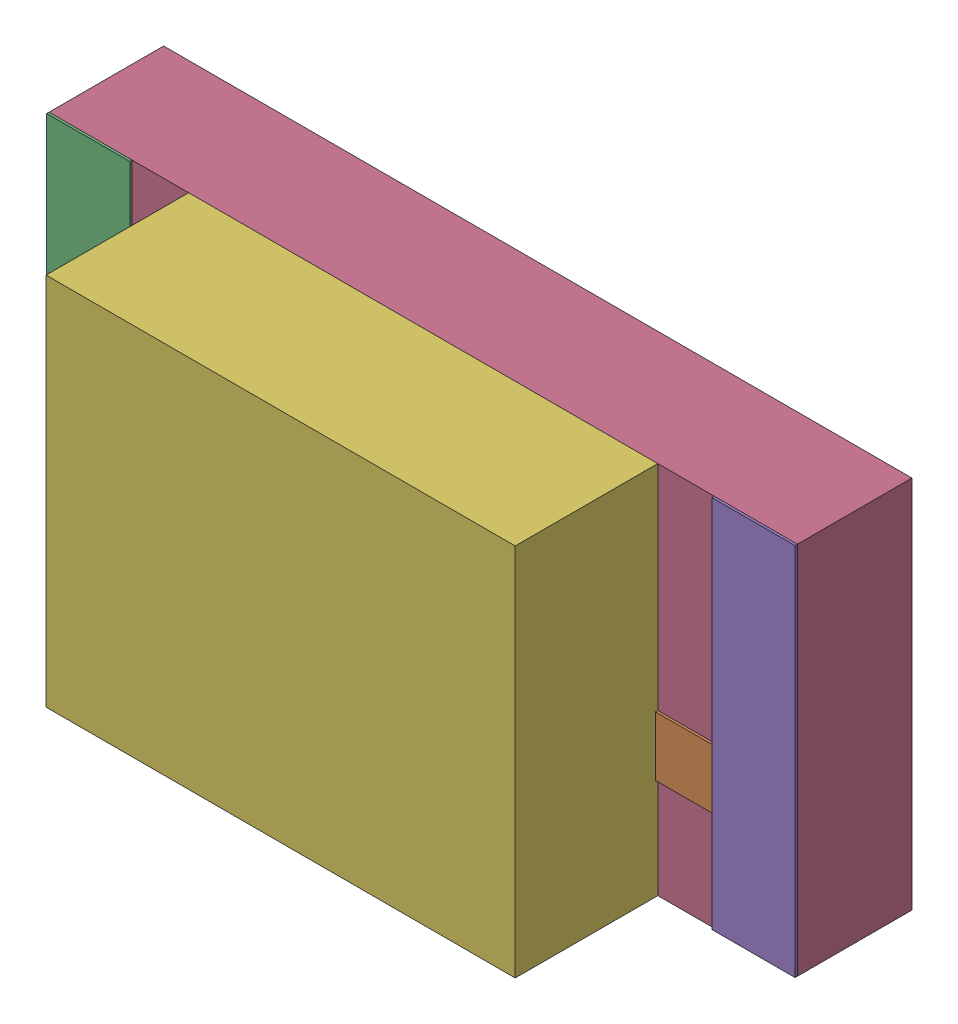
SolidWorks assembly SW3dPS-LED1206G_Open_CASCADE_STEP_translator_6.2_262.2, configuration Défaut. Lengths in mm.
Overall size (3.2 1.6 1.1).
12 component instances, 5 part files, 0 mates.
Components (placement in the parent):
- SW3dPS-LED1206G_352699472-1: SW3dPS-LED1206G_352699472 [Défaut] at (0.6096 0.0254 0.5027) size (0.65 0.76 0.01)
  - SW3dPS-LED1206G_Extruded-1: SW3dPS-LED1206G_Extruded [Défaut] at origin size (0.65 0.76 0.01)
- SW3dPS-LED1206G_352698192-1: SW3dPS-LED1206G_352698192 [Défaut] at (2.1971 0.0254 0.5027) size (1.14 0.76 0.01)
  - SW3dPS-LED1206G_Extruded4-1: SW3dPS-LED1206G_Extruded4 [Défaut] at origin size (1.14 0.76 0.01)
- SW3dPS-LED1206G_352697808-1: SW3dPS-LED1206G_352697808 [Défaut] at (0.1016 0.0127 0.5027) size (0.36 1.6 0.01)
  - SW3dPS-LED1206G_Extruded2-1: SW3dPS-LED1206G_Extruded2 [Défaut] at origin size (0.36 1.6 0.01)
- SW3dPS-LED1206G_352697936-1: SW3dPS-LED1206G_352697936 [Défaut] at (1.524 0.0127 0.0127) size (3.2 1.6 0.49)
  - SW3dPS-LED1206G_Extruded1-1: SW3dPS-LED1206G_Extruded1 [Défaut] at origin size (3.2 1.6 0.49)
- SW3dPS-LED1206G_352697808-2: SW3dPS-LED1206G_352697808 [Défaut] at (2.9464 0.0127 0.5027) size (0.36 1.6 0.01)
  - SW3dPS-LED1206G_Extruded2-1: SW3dPS-LED1206G_Extruded2 [Défaut] at origin size (0.36 1.6 0.01)
- SW3dPS-LED1206G_352700880-1: SW3dPS-LED1206G_352700880 [Défaut] at (1.524 0.0127 0.5027) size (2.01 1.6 0.61)
  - SW3dPS-LED1206G_Extruded3-1: SW3dPS-LED1206G_Extruded3 [Défaut] at origin size (2.01 1.6 0.61)
